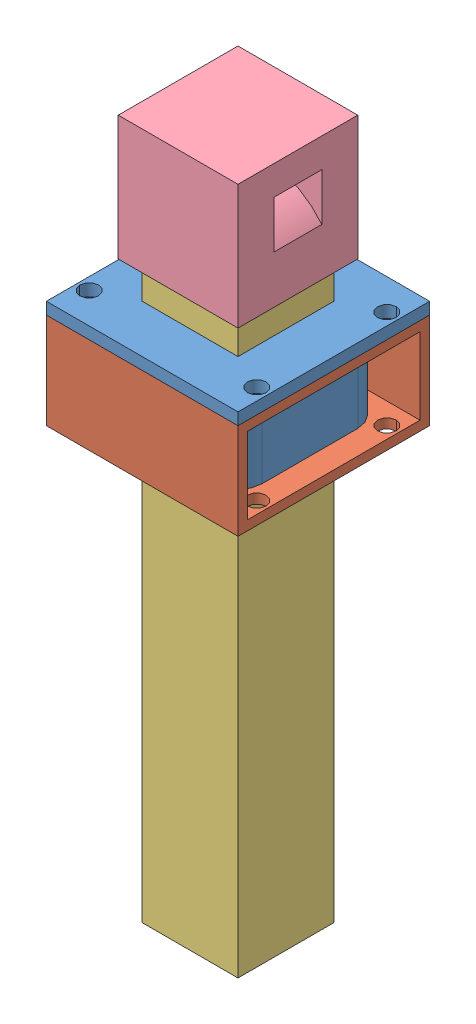
SolidWorks assembly Assem1, configuration Default. Lengths in mm.
Overall size (50.8 185.42 50.8).
4 component instances, 4 part files, 8 mates.
Components (placement in the parent):
- 3d bushing-1: 3d bushing [Default] at (-10.1434 106.6299 7.3214) size (50.8 28.57 50.8)
- Part1-1: Part1 [Default] at (-35.5434 93.9299 7.3214) x (0 0 -1) z (1 0 0) size (50.8 25.4 50.8)
- rod-1: rod [Default] at (-10.1434 -32.8813 7.3214) x (0 0 -1) z (1 0 0) size (25.4 165.1 25.4)
- cap-1: cap [Default] at (-10.1434 136.0287 -8.5536) size (31.75 33.02 31.75)
Mates (geometry in assembly coordinates):
- Coincident3: coincident: plane of 3d bushing-1 through (-10.1434 106.6299 7.3214) normal (0 -1 0); plane of Part1-1 through (15.2566 106.6299 32.7214) normal (0 1 0)
- Coincident4: coincident: plane of 3d bushing-1 through (-22.8434 81.2299 -5.3786) normal (0 0 1); plane of rod-1 through (2.5566 132.2187 -5.3786) normal (0 0 -1)
- Coincident5: coincident: plane of 3d bushing-1 through (2.5566 81.2299 20.0214) normal (-1 0 0); plane of rod-1 through (2.5566 132.2187 20.0214) normal (1 0 0)
- Coincident6: coincident: plane of 3d bushing-1 through (15.2566 109.8049 7.3214) normal (1 0 0); plane of Part1-1 through (15.2566 93.9299 7.3214) normal (1 0 0)
- Coincident7: coincident: plane of 3d bushing-1 through (-10.1434 109.8049 32.7214) normal (0 0 1); plane of Part1-1 through (15.2566 81.2299 32.7214) normal (0 0 1)
- Coincident8: coincident: plane of rod-1 through (2.5566 132.2187 -5.3786) normal (0 0 -1); plane of cap-1 through (-10.1434 136.0287 -5.3786) normal (0 0 1)
- Coincident9: coincident: plane of rod-1 through (-22.8434 132.2187 20.0214) normal (-1 0 0); plane of cap-1 through (-22.8434 136.0287 20.0214) normal (1 0 0)
- Coincident10: coincident: plane of rod-1 through (-10.1434 132.2187 7.3214) normal (0 1 0); plane of cap-1 through (-10.1434 132.2187 20.0214) normal (0 -1 0)
